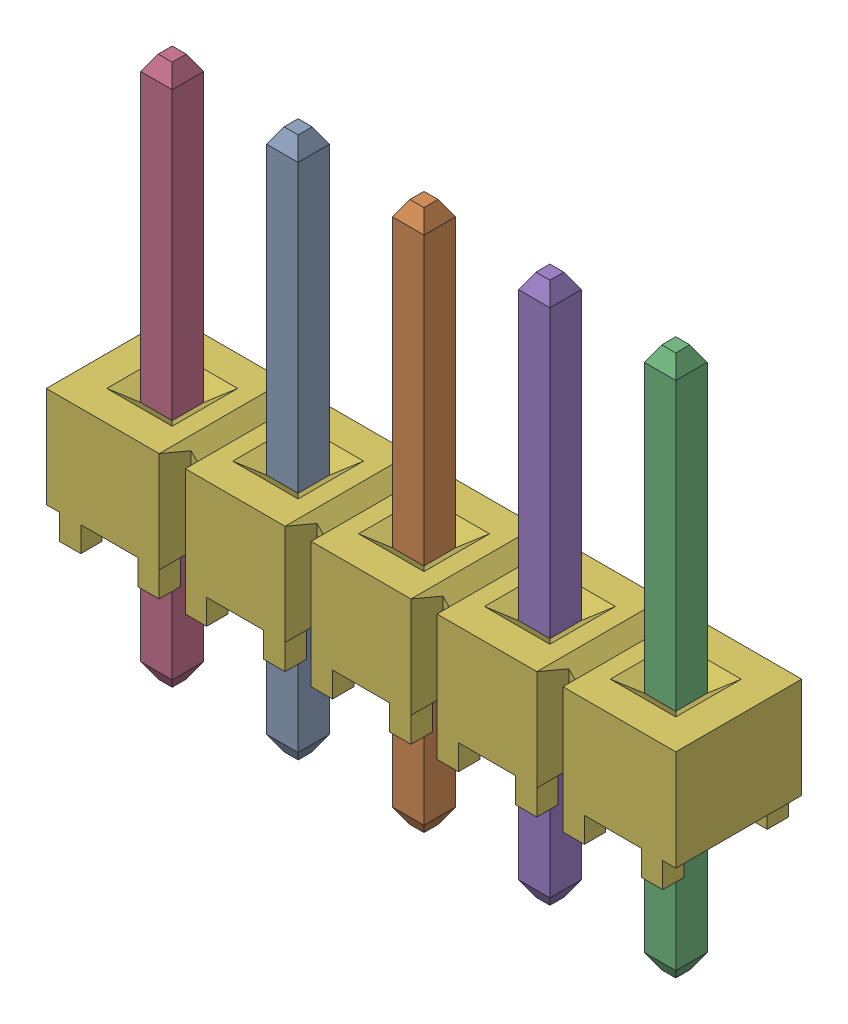
SolidWorks assembly C-L12-1X5_HEADER_ASM, configuration Default. Lengths in mm.
Overall size (12.7 10.92 2.54).
6 component instances, 2 part files, 0 mates.
Components (placement in the parent):
- C-T-HEADER-PIN-1: C-T-HEADER-PIN [Default] at (-6.35 -2.0599 0) x (0 0 1) z (-1 0 0) size (0.64 10.92 0.64)
- C-T-HEADER-PIN-2: C-T-HEADER-PIN [Default] at (-3.81 -2.0599 0) x (0 0 1) z (-1 0 0) size (0.64 10.92 0.64)
- C-T-HEADER-PIN-3: C-T-HEADER-PIN [Default] at (1.27 -2.0599 0) x (0 0 1) z (-1 0 0) size (0.64 10.92 0.64)
- C-T-HEADER-PIN-4: C-T-HEADER-PIN [Default] at (-8.89 -2.0599 0) x (0 0 1) z (-1 0 0) size (0.64 10.92 0.64)
- C-T-HEADER-PIN-5: C-T-HEADER-PIN [Default] at (-1.27 -2.0599 0) x (0 0 1) z (-1 0 0) size (0.64 10.92 0.64)
- C-TSW-XX-S_FORMULA_ANY-5-1: C-TSW-XX-S_FORMULA_ANY-5 [Default] at origin size (12.7 2.54 2.54)
